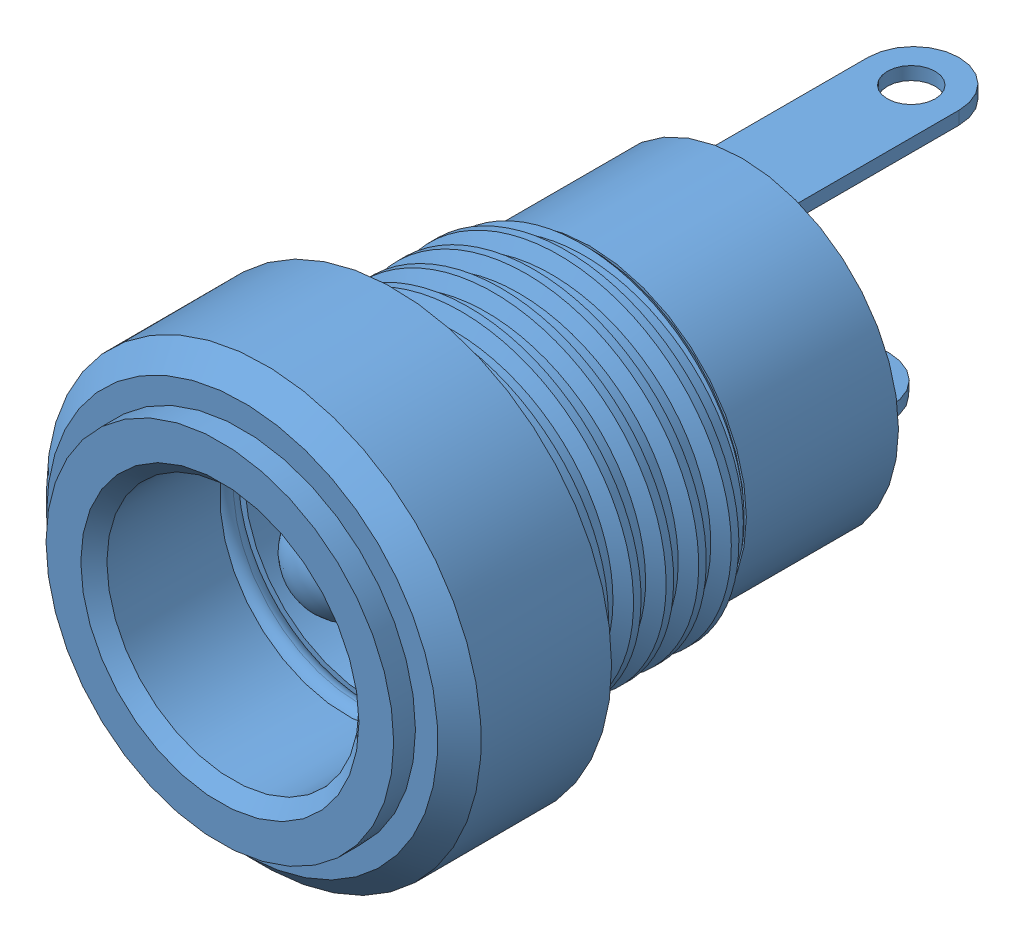
SolidWorks assembly Lumberg_1614_10, configuration Default. Lengths in mm.
Overall size (10 10 17.01).
3 component instances, 2 part files, 3 mates.
Components (placement in the parent):
- Lumberg_1614_10.stp-1: Lumberg_1614_10.stp [Default] at (0.8468 0.2582 0) size (13.42 14.23 17.01)
  - ID_1.stp-1: ID_1.stp [Default] at (-0.8468 -0.2582 0) size (10 10 17.01)
  - ID_1-0.stp-1: ID_1-0.stp [Default] at (-0.8365 -0.3028 -2.0087) x (-0.358368 0.93358 0) z (0 0 1) size (11.4 10 2.51) (hidden)
Mates (geometry in assembly coordinates):
- Coincident1: coincident aligned: plane of Lumberg_1614_10.stp-1 through (0.8468 0.2582 0) normal (0 0 1)
- Coincident2: coincident aligned: plane of Lumberg_1614_10.stp-1/ID_1.stp-1 through (0 0 0) normal (1 0 0)
- Coincident3: coincident aligned: plane of Lumberg_1614_10.stp-1/ID_1.stp-1 through (0 0 0) normal (0 1 0)
